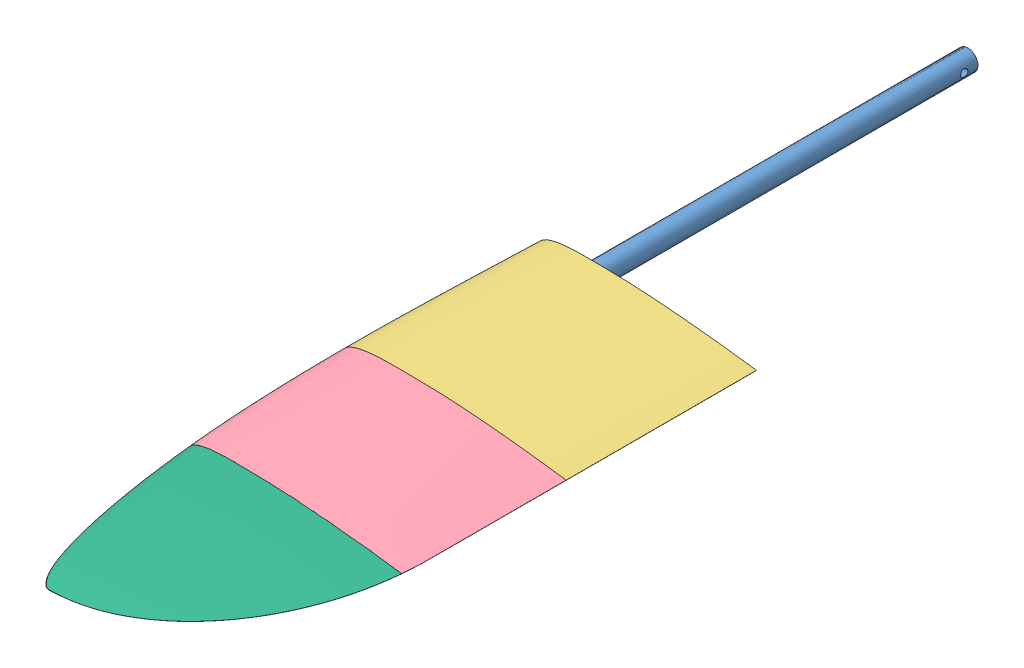
SolidWorks assembly AssembledRudder, configuration Default. Lengths in mm.
Overall size (104.71 12.52 429.01).
6 component instances, 6 part files, 16 mates.
Components (placement in the parent):
- BallJointLinkageRudderShaft-2: BallJointLinkageRudderShaft [Default] at (22.225 0 130.175) x (0 -1 0) z (1 0 0) size (9.53 285.75 9.53)
- RudderDrivePlate-1: RudderDrivePlate [Default] at (30.1625 0 104.775) x (1 0 0) z (0 1 0) size (25.4 50.8 3.17)
- RudderTop-1: RudderTop [Default] at (-3.175 0 19.558) size (104.71 12.52 89.01)
- RudderMiddle-1: RudderMiddle [Default] at (-3.175 0 19.558) size (104.7 12.44 76.26)
- RudderTipCoupler-1: RudderTipCoupler [Default] at (21.971 1.397 184.5945) x (0 0 1) z (1 0 0) size (12.57 2.41 25.27)
- RudderTip-1: RudderTip [Default] at (-3.175 0 19.431) size (101.87 12.42 88.9)
Mates (geometry in assembly coordinates):
- Coincident1: coincident aligned: line of ? through (12.7 1.5875 38.1) axis (0 0 -1); line of ? through (12.7 1.5875 44.45) axis (0 0 -1)
- Coincident2: coincident anti-aligned: line of ? through (31.75 1.5875 38.1) axis (-1 0 0); line of ? through (12.7 1.5875 38.1) axis (1 0 0)
- Coincident3: coincident anti-aligned: plane of BallJointLinkageRudderShaft-2 through (17.4625 -1.5875 180.975) normal (0 1 0); plane of RudderDrivePlate-1 through (30.1625 -1.5875 104.775) normal (0 -1 0)
- Tangent1: tangent aligned: cylinder of BallJointLinkageRudderShaft-2 through (22.225 0 -155.575) axis (0 0 1) radius 4.7625; plane of RudderDrivePlate-1 through (17.4625 1.5875 130.175) normal (-1 0 0)
- Coincident4: coincident aligned: plane of BallJointLinkageRudderShaft-2 through (22.225 0 130.175) normal (0 0 1); plane of RudderDrivePlate-1 through (42.8625 1.5875 130.175) normal (0 0 1)
- Concentric1: concentric anti-aligned: cylinder of ? through (22.225 0 130.175) axis (0 0 -1) radius 4.7625; cylinder of BallJointLinkageRudderShaft-2 through (22.225 0 -155.575) axis (0 0 1) radius 4.7625
- Coincident5: coincident anti-aligned: line of ? through (42.8625 -1.5875 130.175) axis (-1 0 0); line of RudderDrivePlate-1 through (17.4625 -1.5875 130.175) axis (1 0 0)
- Concentric2: concentric anti-aligned: cylinder of BallJointLinkageRudderShaft-2 through (22.225 0 -155.575) axis (0 0 1) radius 4.7625; cylinder of RudderTop-1 through (22.225 0 130.683) axis (0 0 -1) radius 4.8895
- Distance1: distance = 0.127 mm: line of RudderDrivePlate-1 through (42.8625 1.5875 79.375) axis (-1 0 0); line of RudderTop-1 through (49.0855 1.7145 79.375) axis (-1 0 0)
- Concentric3: concentric anti-aligned: cylinder of BallJointLinkageRudderShaft-2 through (22.225 0 -155.575) axis (0 0 1) radius 4.7625; cylinder of RudderMiddle-1 through (22.225 0 130.683) axis (0 0 -1) radius 4.8895
- Coincident9: coincident anti-aligned: line of RudderMiddle-1 through (9.3345 1.397 178.308) axis (0 -1 0); line of RudderTipCoupler-1 through (9.3345 -1.016 178.308) axis (0 1 0)
- Coincident10: coincident anti-aligned: line of RudderMiddle-1 through (35.1155 1.397 178.308) axis (-1 0 0); line of RudderTipCoupler-1 through (9.3345 1.397 178.308) axis (1 0 0)
- Coincident11: coincident anti-aligned: line of RudderTipCoupler-1 through (34.6075 1.397 190.881) axis (-1 0 0); line of RudderTip-1 through (9.3345 1.397 190.881) axis (1 0 0)
- Coincident12: coincident anti-aligned: line of RudderTipCoupler-1 through (9.3345 -1.016 190.881) axis (0 1 0); line of RudderTip-1 through (9.3345 1.397 190.881) axis (0 -1 0)
- Parallel1: parallel anti-aligned: plane of RudderDrivePlate-1 through (30.1625 -1.5875 104.775) normal (0 -1 0); plane of RudderMiddle-1 through (-3.175 -1.7145 130.683) normal (0 1 0)
- Coincident14: coincident anti-aligned: plane of RudderTop-1 through (-3.175 0 108.458) normal (0 0 1); plane of RudderMiddle-1 through (-3.175 0 108.458) normal (0 0 -1)
